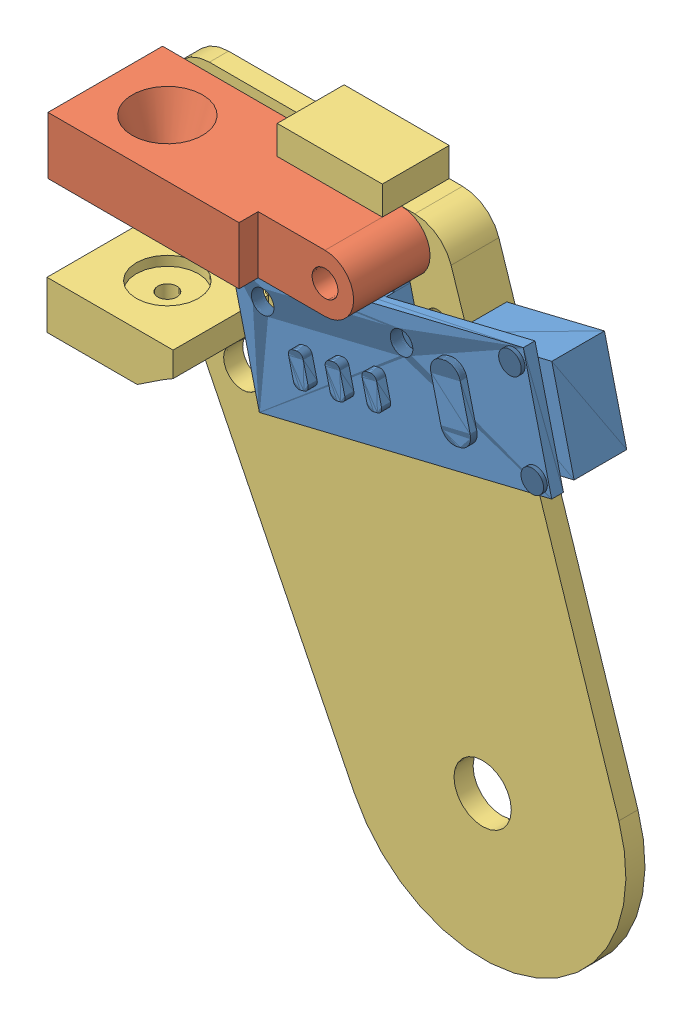
SolidWorks assembly limit_assembly, configuration Default. Lengths in mm.
Overall size (82.8 107.95 19.05).
3 component instances, 3 part files, 4 mates.
Components (placement in the parent):
- mechanical_endstop-1: mechanical_endstop [Default] at (58.8161 21.2263 -22.6708) x (0.971653 0.236413 0) z (0 0 -1) size (41.88 19.5 9.76)
- lever_bar-1: lever_bar [Default] at (59.5905 30.3176 -27.4208) size (38.1 7.62 15.24)
- limit_plate3-1: limit_plate3 [Default] at (83.7195 -31.9124 -33.7708) size (82.8 107.95 19.05)
Mates (geometry in assembly coordinates):
- Coincident10: coincident anti-aligned: plane of mechanical_endstop-1 through (58.8161 21.2263 -31.2308) normal (0 0 -1); plane of limit_plate3-1 through (83.7195 -31.9124 -31.2308) normal (0 0 1)
- Distance1: distance = 3.81 mm anti-aligned: plane of lever_bar-1 through (76.7355 30.3176 -27.4208) normal (0 0 -1); plane of limit_plate3-1 through (83.7195 -31.9124 -31.2308) normal (0 0 1)
- Coincident12: coincident aligned: plane of lever_bar-1 through (42.4455 34.1276 -17.2608) normal (0 1 0); plane of limit_plate3-1 through (42.3175 34.1276 -31.2308) normal (0 1 0)
- Distance2: distance = 0.254 mm anti-aligned: plane of mechanical_endstop-1 through (58.8161 26.2536 -22.6708) normal (0 1 0); plane of lever_bar-1 through (42.4455 26.5076 -17.2608) normal (0 -1 0)
